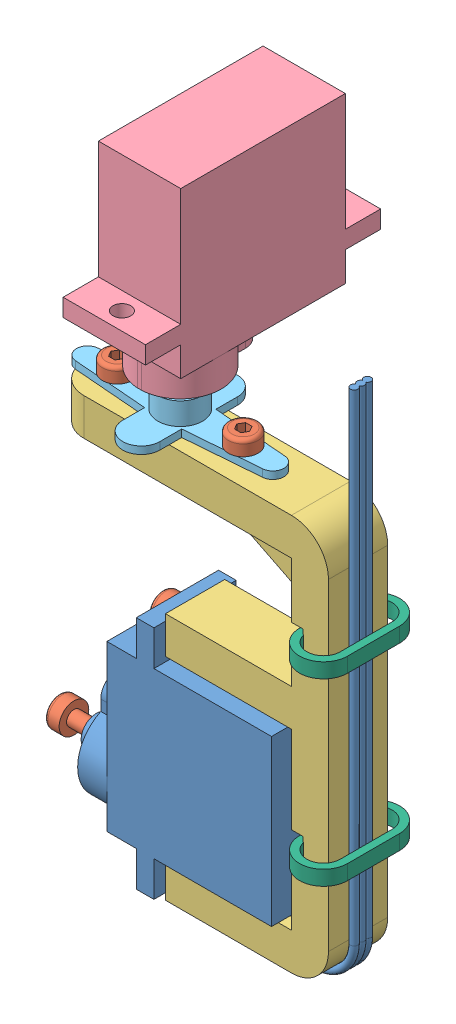
SolidWorks assembly wheel assembly_right, configuration základní. Lengths in mm.
Overall size (42.45 86.59 31.75).
12 component instances, 6 part files, 30 mates.
Components (placement in the parent):
- servo9g-3: servo9g [zakladni] at (17.875 -1.8062 33.875) x (0 1 0) z (-1 0 0) size (70.5 11.11 36.23)
- ŠROUB M2 x 12 až 150 DIN 912 A2-1: ŠROUB M2 x 12 až 150 DIN 912 A2 [M2x6] at (-14.35 -7.2082 33.875) x (0 -0.871054 -0.491187) z (-1 0 0) size (7.77 4 8)
- wheel_holder-1: wheel_holder [Výchozí] at (2 -13.3394 33.875) size (37 53.5 8)
- servo9g_2-2: servo9g_2 [zakladni] at (0 67.3856 28.473) x (0 0 -1) z (0 -1 0) size (31.75 11.11 29.23)
- paka-1: paka [Výchozí] at (0 35.1606 33.875) size (28 4 15.5)
- ŠROUB M2 x 12 až 150 DIN 912 A2-5: ŠROUB M2 x 12 až 150 DIN 912 A2 [M2x6] at (0 35.1606 33.875) x (-0.5 0 0.866025) z (0 -1 0) size (7.77 4 8)
- ŠROUB M2 x 12 až 150 DIN 912 A2-3: ŠROUB M2 x 12 až 150 DIN 912 A2 [M2x6] at (8.5 36.1606 33.875) x (0.5 0 0.866025) z (0 1 0) size (7.77 4 8)
- ŠROUB M2 x 12 až 150 DIN 912 A2-4: ŠROUB M2 x 12 až 150 DIN 912 A2 [M2x6] at (-8.5 36.1606 33.875) x (0.5 0 0.866025) z (0 1 0) size (7.77 4 8)
- sponka-1: sponka [Výchozí] at (22.85 20.0106 33.875) x (0 0 1) z (-1 0 0) size (13.5 2 6.5)
- sponka-2: sponka [Výchozí] at (22.85 -4.2394 33.875) x (0 0 1) z (-1 0 0) size (13.5 2 6.5)
- ŠROUB M2 x 12 až 150 DIN 912 A2-6: ŠROUB M2 x 12 až 150 DIN 912 A2 [M2x6] at (-0.3813 11.9043 33.8749) x (0 0 1) z (-1 0 0) size (7.77 4 8)
- ŠROUB M2 x 12 až 150 DIN 912 A2-7: ŠROUB M2 x 12 až 150 DIN 912 A2 [M2x6] at (-0.3813 -15.0832 33.8749) x (0 0 1) z (-1 0 0) size (7.77 4 8)
Mates (geometry in assembly coordinates):
- Sjednocená10: coincident anti-aligned: plane of servo9g-3 through (2 -17.4644 28.32) normal (1 0 0); plane of wheel_holder-1 through (2 -18.3394 37.875) normal (-1 0 0)
- Soustředná3: concentric aligned: cylinder of wheel_holder-1 through (0 20.1606 33.875) axis (0 1 0) radius 3; cylinder of servo9g_2-2 through (0 38.1606 33.875) axis (0 1 0) radius 2.0388
- Sjednocená14: coincident anti-aligned: plane of servo9g-3; plane of wheel_holder-1 through (2 -13.3394 33.875) normal (0 0 1)
- Soustředná4: concentric anti-aligned: cylinder of servo9g_2-2 through (0 38.1606 33.875) axis (0 1 0) radius 2.0388; cylinder of paka-1 through (0 36.1606 33.875) axis (0 -1 0) radius 2
- Sjednocená15: coincident anti-aligned: plane of wheel_holder-1 through (2 35.1606 33.875) normal (0 1 0); plane of paka-1 through (12.5 35.1606 33.875) normal (0 -1 0)
- Sjednocená16: coincident aligned: plane of wheel_holder-1 through (2 -13.3394 33.875) normal (0 0 1); plane of paka-1 through (0 35.1606 33.875) normal (0 0 1)
- Rovnoběžná2: parallel aligned: plane of wheel_holder-1 through (2 -13.3394 37.875) normal (0 0 1); plane of ŠROUB M2 x 12 až 150 DIN 912 A2-5 through (-0.433 35.1606 33.125) normal (0 0 1)
- Sjednocená18: coincident anti-aligned: plane of paka-1 through (12.5 35.1606 33.875) normal (0 -1 0); plane of ŠROUB M2 x 12 až 150 DIN 912 A2-5 through (0 35.1606 33.875) normal (0 1 0)
- Sjednocená19: coincident anti-aligned: plane of servo9g_2-2 through (0 41.1606 28.473) normal (0 -1 0); plane of ŠROUB M2 x 12 až 150 DIN 912 A2-5 through (0 41.1606 33.875) normal (0 1 0)
- Soustředná6: concentric aligned: cylinder of paka-1 through (-8.5 34.1606 33.875) axis (0 1 0) radius 1.15; cylinder of ŠROUB M2 x 12 až 150 DIN 912 A2-4 through (-8.5 30.1606 33.875) axis (0 1 0) radius 1
- Soustředná7: concentric aligned: cylinder of paka-1 through (8.5 34.1606 33.875) axis (0 1 0) radius 1.15; cylinder of ŠROUB M2 x 12 až 150 DIN 912 A2-3 through (8.5 30.1606 33.875) axis (0 1 0) radius 1
- Sjednocená20: coincident anti-aligned: plane of paka-1 through (12.5 36.1606 33.875) normal (0 1 0); plane of ŠROUB M2 x 12 až 150 DIN 912 A2-4 through (-8.5 36.1606 33.875) normal (0 -1 0)
- Sjednocená21: coincident anti-aligned: plane of paka-1 through (12.5 36.1606 33.875) normal (0 1 0); plane of ŠROUB M2 x 12 až 150 DIN 912 A2-3 through (8.5 36.1606 33.875) normal (0 -1 0)
- Rovnoběžná3: parallel aligned: plane of ŠROUB M2 x 12 až 150 DIN 912 A2-4 through (-8.067 36.1606 33.125) normal (0 0 1); plane of wheel_holder-1 through (2 -13.3394 37.875) normal (0 0 1)
- Rovnoběžná4: parallel aligned: plane of ŠROUB M2 x 12 až 150 DIN 912 A2-4 through (-8.067 36.1606 33.125) normal (0 0 1); plane of ŠROUB M2 x 12 až 150 DIN 912 A2-3 through (8.933 36.1606 33.125) normal (0 0 1)
- Vystředění1: width aligned: plane of wheel_holder-1 through (2 -13.3394 37.875) normal (0 1 0); plane of wheel_holder-1 through (19 10.1606 37.875) normal (0 -1 0); plane of servo9g-3 through (17.875 9.5231 28.32) normal (0 1 0); plane of servo9g-3 through (2 -12.7019 28.32) normal (0 -1 0)
- Soustředná8: concentric aligned: cylinder of wheel_holder-1 through (0 20.1606 33.875) axis (0 1 0) radius 3; circle of ŠROUB M2 x 12 až 150 DIN 912 A2-5
- Sjednocená22: coincident anti-aligned: plane of wheel_holder-1 through (20.6 22.6606 27.875) normal (-1 0 0); plane of sponka-1 through (20.6 22.0106 30.375) normal (1 0 0)
- Sjednocená24: coincident aligned: plane of wheel_holder-1 through (2 -13.3394 33.875) normal (0 0 1); plane of sponka-1 through (22.85 20.0106 33.875) normal (0 0 1)
- Vystředění2: width anti-aligned: plane of wheel_holder-1 through (19 22.6606 27.875) normal (0 -1 0); plane of wheel_holder-1 through (19 19.3606 27.875) normal (0 1 0); plane of sponka-1 through (22.85 22.0106 30.375) normal (0 1 0); plane of sponka-1 through (22.85 20.0106 30.375) normal (0 -1 0)
- Soustředná9: concentric aligned: cylinder of sponka-1 through (22.85 22.0106 37.375) axis (0 -1 0) radius 3.25; cylinder of sponka-2 through (22.85 -2.2394 37.375) axis (0 -1 0) radius 3.25
- Sjednocená25: coincident anti-aligned: plane of wheel_holder-1 through (20.6 -1.5894 27.875) normal (-1 0 0); plane of sponka-2 through (20.6 -2.2394 30.375) normal (1 0 0)
- Vystředění3: width anti-aligned: plane of wheel_holder-1 through (19 -4.8894 27.875) normal (0 1 0); plane of wheel_holder-1 through (19 -1.5894 27.875) normal (0 -1 0); plane of sponka-2 through (22.85 -4.2394 30.375) normal (0 -1 0); plane of sponka-2 through (22.85 -2.2394 30.375) normal (0 1 0)
- Mezní úhel1: limit planar angle = 1.570796 rad aligned: plane of servo9g_2-2 through (5.555 67.3856 28.473) normal (1 0 0); plane of wheel_holder-1 through (2 -13.3394 29.875) normal (0 0 -1)
- Soustředná10: concentric anti-aligned: cylinder of servo9g-3 through (-11.35 -7.2082 33.875) axis (1 0 0) radius 1.2452; cylinder of ŠROUB M2 x 12 až 150 DIN 912 A2-1 through (-8.35 -7.2082 33.875) axis (-1 0 0) radius 1
- Vzdálenost1: distance = 3 mm anti-aligned: plane of servo9g-3 through (-11.35 -7.2082 33.875) normal (-1 0 0); plane of ŠROUB M2 x 12 až 150 DIN 912 A2-1 through (-14.35 -7.2082 33.875) normal (1 0 0)
- Soustředná11: concentric aligned: cylinder of servo9g-3 through (22.6187 11.9043 33.8749) axis (-1 0 0) radius 1.1906; cylinder of ŠROUB M2 x 12 až 150 DIN 912 A2-6 through (5.6187 11.9043 33.8749) axis (-1 0 0) radius 1
- Sjednocená26: coincident aligned: plane of servo9g-3 through (-0.3813 14.2856 28.32) normal (-1 0 0); circle of ŠROUB M2 x 12 až 150 DIN 912 A2-6
- Soustředná12: concentric aligned: cylinder of servo9g-3 through (22.6187 -15.0832 33.8749) axis (-1 0 0) radius 1.1906; cylinder of ŠROUB M2 x 12 až 150 DIN 912 A2-7 through (5.6187 -15.0832 33.8749) axis (-1 0 0) radius 1
- Sjednocená27: coincident aligned: plane of servo9g-3 through (-0.3813 -12.7019 28.32) normal (-1 0 0); circle of ŠROUB M2 x 12 až 150 DIN 912 A2-7
